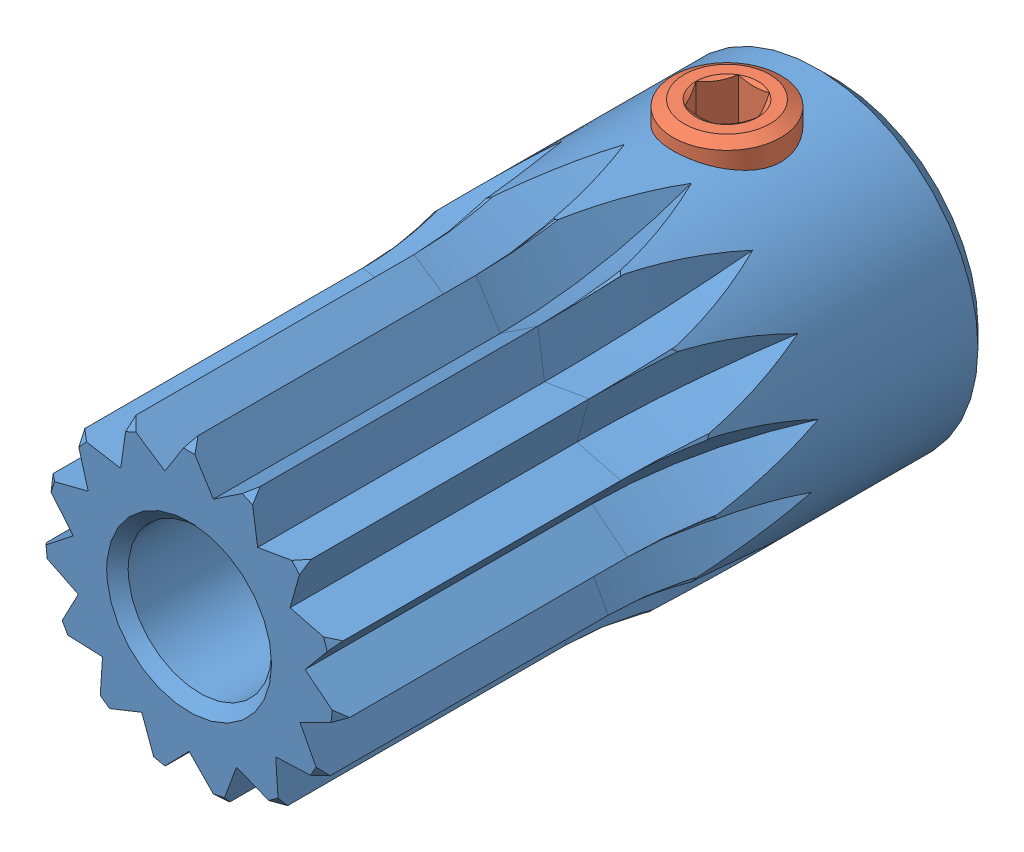
SolidWorks assembly GEABP0_5_15_8_K_4, configuration Default. Lengths in mm.
Overall size (9 9.5 18).
2 component instances, 2 part files, 0 mates.
Components (placement in the parent):
- GEABP0_5_15_8_K_4_b-1: GEABP0_5_15_8_K_4_b [Default] x (-1 0 0) z (0 0 -1) size (9 9 18)
- Hexagon_socket_set_screw_with_flat_point_DIN_913___M3x3-1: Hexagon_socket_set_screw_with_flat_point_DIN_913___M3x3 [Default] at (0 5 -15) x (0 -1 0) z (1 0 0) size (3 3 3)
